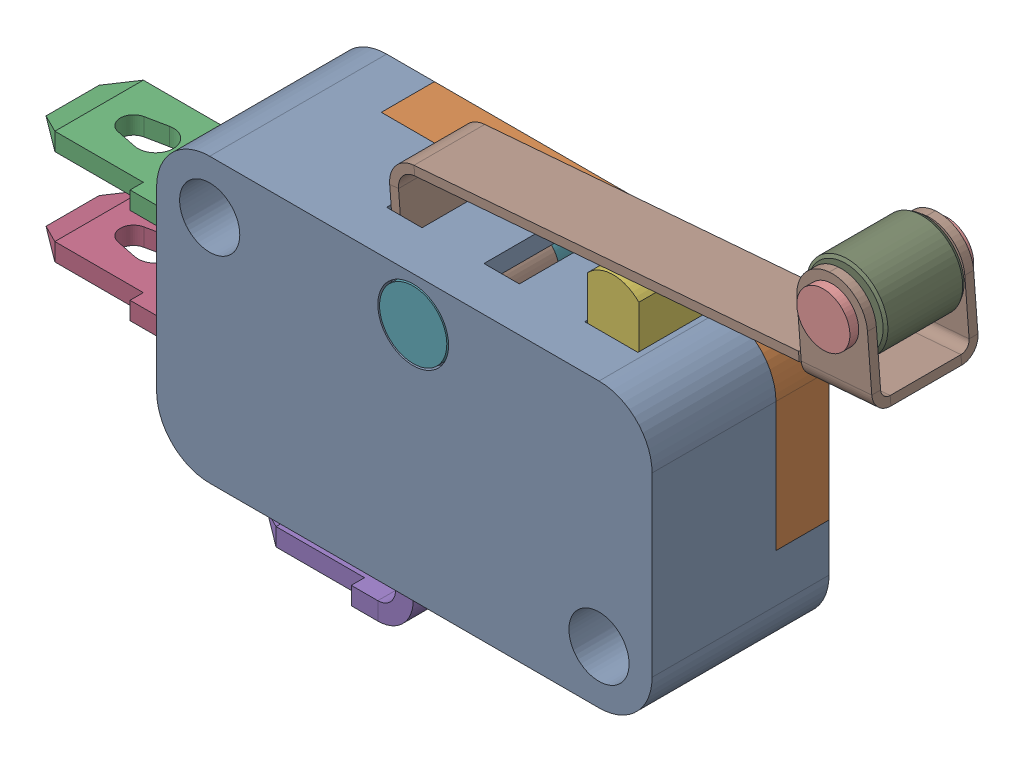
SolidWorks assembly Final1masterAssembly - V-156-1C25 micro switch, configuration Idle. Lengths in mm.
Overall size (48.75 30.4 10).
10 component instances, 9 part files, 25 mates.
Components (placement in the parent):
- Final1masterBody-1: Final1masterBody [Domyślna] at origin size (28 16 10)
- Final1masterCover-1: Final1masterCover [Domyślna] at (0 0 3) x (-1 0 0) z (0 0 -1) size (28 16 3)
- Final1masterConnector - straight-1: Final1masterConnector - straight [Domyślna] at (-13 2.1 4.75) x (-1 0 0) z (0 -1 0) size (11 6.5 1)
- Final1masterConnector - straight-2: Final1masterConnector - straight [Domyślna] at (-13 -4.3 4.75) x (-1 0 0) z (0 1 0) size (11 6.5 1)
- Final1masterConnector - bent-1: Final1masterConnector - bent [Domyślna] at (-0.5 -11 4.75) x (-1 0 0) z (0 -1 0) size (10 6.5 5)
- Final1masterSwitch-2: Final1masterSwitch [Domyślna] at (9.2 8.4387 3.1) size (3.9 4.5 4.3)
- Final1masterRivet - long-1: Final1masterRivet - long [Domyślna] at (0.5 5.5 10) x (0 0 -1) z (0.574772 -0.818314 0) size (10 4 4)
- Final1masterArm-2: Final1masterArm [Domyślna] at (0 0 5) x (-1 0 0) z (0 0 -1) size (28.33 14.28 6)
- Final1masterRoll-1: Final1masterRoll [Domyślna] at (22.4283 16.0971 3) size (4.6 4.6 4.5)
- Final1masterRivet - short-1: Final1masterRivet - short [Domyślna] at (22.4283 16.0971 8.75) x (0 0 -1) z (1 0 0) size (7 3 3)
Mates (geometry in assembly coordinates):
- Koncentryczne1: concentric anti-aligned: cylinder of masterBody-1 through (-11 5 9) axis (0 0 -1) radius 2.7; cylinder of masterCover-1 through (-11 5 0) axis (0 0 1) radius 2.7
- Koncentryczne2: concentric anti-aligned: cylinder of masterBody-1 through (11 -5 9) axis (0 0 -1) radius 2.7; cylinder of masterCover-1 through (11 -5 0) axis (0 0 1) radius 2.7
- Wspólnie1: coincident anti-aligned: plane of masterBody-1 through (11 5 3) normal (0 0 -1); plane of masterCover-1 through (11 5 3) normal (0 0 1)
- Wspólnie2: coincident anti-aligned: plane of masterBody-1 through (14.001 2.1 3) normal (0 -1 0); plane of Connector - straight-1 through (-13 2.1 4.75) normal (0 1 0)
- Wspólnie3: coincident aligned: plane of masterBody-1 through (-13 1.3 9) normal (1 0 0); plane of Connector - straight-1 through (-13 1.1 8) normal (1 0 0)
- Wspólnie4: coincident anti-aligned: plane of masterCover-1 through (14.001 2.1 1.5) normal (0 0 1); plane of Connector - straight-1 through (-13 1.1 1.5) normal (0 0 -1)
- Wspólnie5: coincident anti-aligned: plane of masterBody-1 through (14.001 -3.3 3) normal (0 -1 0); plane of Connector - straight-2 through (-13 -3.3 4.75) normal (0 1 0)
- Wspólnie6: coincident aligned: plane of masterBody-1 through (-13 1.3 9) normal (1 0 0); plane of Connector - straight-2 through (-13 -3.3 1.5) normal (1 0 0)
- Wspólnie7: coincident anti-aligned: plane of masterCover-1 through (14.001 -3.3 1.5) normal (0 0 1); plane of Connector - straight-2 through (-13 -3.3 1.5) normal (0 0 -1)
- Wspólnie8: coincident aligned: plane of masterBody-1 through (-11 -7 9) normal (0 1 0); plane of Connector - bent-1 through (-2.5 -7 8) normal (0 1 0)
- Wspólnie9: coincident anti-aligned: plane of masterCover-1 through (-1.5 8.001 1.5) normal (0 0 1); plane of Connector - bent-1 through (-2.5 -7 1.5) normal (0 0 -1)
- Wspólnie10: coincident anti-aligned: plane of masterBody-1 through (-1.5 8.001 3) normal (-1 0 0); plane of Connector - bent-1 through (-1.5 -7 8) normal (1 0 0)
- Symetrycznie1: symmetric aligned: plane of masterBody-1 through (7.7 -8.001 7.5) normal (0 0 -1); plane of Switch-2 through (11 5 3) normal (0 0 1); plane of masterCover-1 through (9.2 8.4387 5.25) normal (0 0 1)
- Wspólnie11: coincident anti-aligned: plane of masterBody-1 through (11 7 9) normal (0 -1 0); plane of Switch-2 through (7.75 7 7.4) normal (0 1 0)
- Symetrycznie2: symmetric aligned: plane of masterBody-1 through (10.7 -8.001 3) normal (-1 0 0); plane of Switch-2 through (7.7 -8.001 3) normal (1 0 0); plane of masterBody-1 through (9.2 8.4387 3.1) normal (1 0 0)
- Koncentryczne3: concentric aligned: cylinder of masterBody-1 through (0.5 5.5 -0.001) axis (0 0 1) radius 1; cylinder of Rivet - long-1 through (0.5 5.5 0.5) axis (0 0 1) radius 1
- Wspólnie12: coincident anti-aligned: plane of masterCover-1 through (0.5 5.5 0.5) normal (0 0 -1); plane of Rivet - long-1 through (1.3183 6.0748 0.5) normal (0 0 1)
- Koncentryczne4: concentric anti-aligned: cylinder of Rivet - long-1 through (0.5 5.5 0.5) axis (0 0 1) radius 1; cylinder of Arm-2 through (0.5 5.5 7.25) axis (0 0 -1) radius 1.5
- Stycznie1: tangent anti-aligned: cylinder of Switch-2 through (9.2 9 7.4) axis (0 0 -1) radius 2; plane of Arm-2 through (24.7464 12.2726 7.25) normal (0.081165 -0.996701 0)
- Odległość1: distance = 0.25 mm anti-aligned: plane of masterCover-1 through (11 5 3) normal (0 0 1); plane of Arm-2 through (-2.1645 10.0812 3.25) normal (0 0 -1)
- Koncentryczne5: concentric aligned: cylinder of Arm-2 through (22.4283 16.0971 8.25) axis (0 0 -1) radius 1; cylinder of Roll-1 through (22.4283 16.0971 7.5) axis (0 0 -1) radius 1
- Symetrycznie3: symmetric aligned: plane of Arm-2 through (0 0 2.25) normal (0 0 -1); plane of Roll-1 through (0 0 8.25) normal (0 0 1); plane of Arm-2 through (22.4283 16.0971 5.25) normal (0 0 1)
- Koncentryczne6: concentric anti-aligned: cylinder of Arm-2 through (22.4283 16.0971 8.25) axis (0 0 -1) radius 1; cylinder of Rivet - short-1 through (22.4283 16.0971 2.25) axis (0 0 1) radius 1
- Wspólnie17: coincident anti-aligned: plane of Arm-2 through (0 0 8.25) normal (0 0 1); plane of Rivet - short-1 through (22.4283 17.5971 8.25) normal (0 0 -1)
- Stycznie2: tangent anti-aligned: cylinder of Body-1 through (11 5 10) axis (0 0 -1) radius 3; plane of Arm-2 through (24.7464 12.2726 7.25) normal (0.081165 -0.996701 0)
